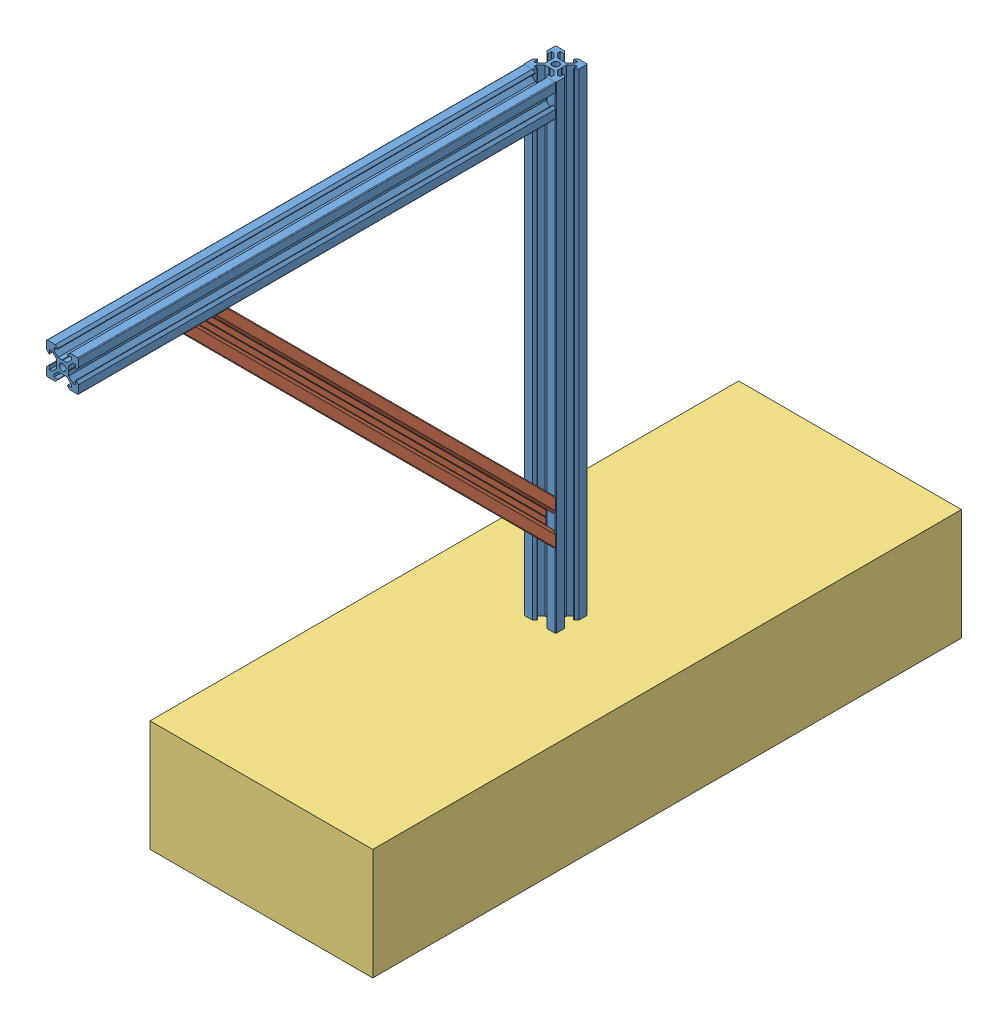
SolidWorks assembly Assem1, configuration Default. Lengths in mm.
Overall size (140 370 495).
4 component instances, 3 part files, 10 mates.
Components (placement in the parent):
- 250mm-1: 250mm [Default] at (-106.0018 493.5821 -883.5082) size (20 20 300)
- 250mm-2: 250mm [Default] at (-106.0018 203.5821 -893.5082) x (-1 0 0) z (0 1 0) size (20 20 300)
- 45deg-1: 45deg [Default] at (-255.875 147.4015 -1007.5568) x (-1 0 0) z (0 0.707107 0.707107) size (20 20 330.76)
- Vallon VMC1-1: Vallon VMC1 [Default] at (-106.0018 168.5821 -893.5082) x (0 0 -1) z (1 0 0) size (370 70 140)
Mates (geometry in assembly coordinates):
- Coincident1: coincident aligned: plane of 250mm-1 through (-106.0018 503.5821 -383.5082) normal (0 1 0); plane of 250mm-2 through (-106.0018 503.5821 -893.5082) normal (0 1 0)
- Coincident2: coincident aligned: plane of 250mm-1 through (-96.0018 493.5821 -383.5082) normal (1 0 0); plane of 250mm-2 through (-96.0018 703.5821 -893.5082) normal (1 0 0)
- Coincident3: coincident anti-aligned: plane of 250mm-1 through (-106.0018 483.5821 -383.5082) normal (0 -1 0); plane of 45deg-1 through (-255.875 483.5821 -1007.5568) normal (0 1 0)
- Coincident4: coincident anti-aligned: plane of 250mm-1 through (-106.0018 493.5821 -883.5082) normal (0 0 -1); plane of 250mm-2 through (-106.0018 703.5821 -883.5082) normal (0 0 1)
- Coincident5: coincident anti-aligned: plane of 250mm-2 through (-106.0018 703.5821 -883.5082) normal (0 0 1); plane of 45deg-1 through (-255.875 147.4015 -883.5082) normal (0 0 -1)
- Parallel1: parallel aligned: plane of 250mm-2 through (-106.0018 703.5821 -903.5082) normal (0 0 -1); plane of Vallon VMC1-1 through (-176.0018 203.5821 -1078.5082) normal (0 0 -1)
- Coincident6: coincident: plane of 250mm-2 through (-106.0018 203.5821 -893.5082) normal (0 0 1); moEndPointRef_w of Vallon VMC1-1
- Coincident7: coincident: plane of 250mm-2 through (-106.0018 203.5821 -893.5082) normal (-1 0 0); moEndPointRef_w of Vallon VMC1-1
- Coincident8: coincident anti-aligned: plane of 250mm-2 through (-106.0018 203.5821 -893.5082) normal (0 -1 0); plane of Vallon VMC1-1 through (-106.0018 203.5821 -893.5082) normal (0 1 0)
- Coincident9: coincident aligned: plane of 250mm-1 through (-96.0018 493.5821 -383.5082) normal (1 0 0); plane of 45deg-1 through (-96.0018 550.4887 -596.8615) normal (1 0 0)
